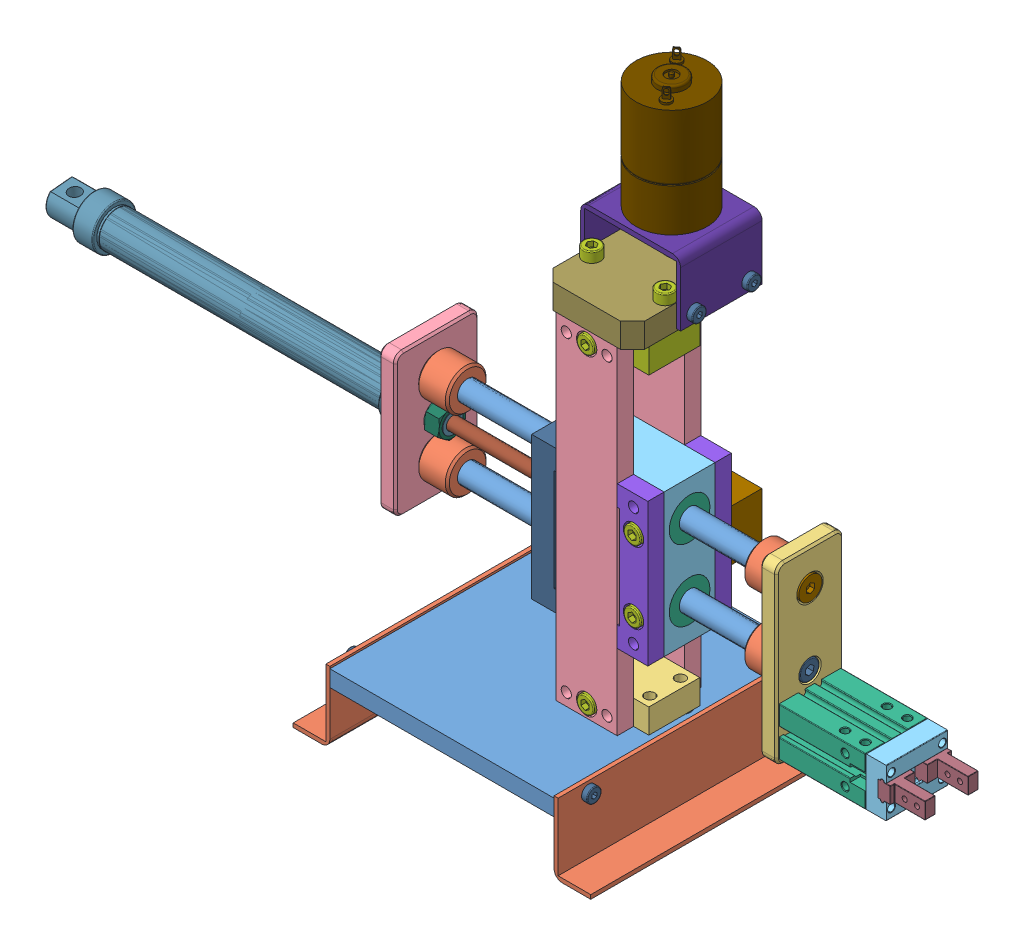
SolidWorks assembly handling, configuration Default. Lengths in mm.
Overall size (436.7 290 125).
70 component instances, 33 part files, 172 mates.
Components (placement in the parent):
- tam de lon-1: tam de lon [Default] at (42.5889 56.6685 101.1963) size (110 8 125)
- khoi do-1: khoi do [Default] at (98.4472 49.4552 163.6963) x (0 0 -1) z (-1 0 0) size (125 35 18)
- khoi do-2: khoi do [Default] at (-13.2695 49.4552 38.6963) x (0 0 1) z (1 0 0) size (125 35 18)
- mieng dem duoi-1: mieng dem duoi [Default] at (71.5889 64.6685 101.1963) size (45 12 25)
- thanh dan huong lon x2-1: thanh dan huong lon x2 [Default] at (71.5889 147.1685 113.6963) x (1 0 0) z (0 -1 0) size (30 8 165)
- thanh dan huong lon x2-2: thanh dan huong lon x2 [Default] at (71.5889 147.1685 88.6963) x (1 0 0) z (0 1 0) size (30 8 165)
- con truot s4 -1: con truot s4  [Default] at (79.0889 101.791 101.1963) x (-1 0 0) z (0 0 -1) size (45 70 25)
- bac lot-1: bac lot [Default] at (101.5889 119.291 101.1963) x (0 1 0) z (0 0 1) size (20 12 20)
- bac lot-2: bac lot [Default] at (101.5889 154.291 101.1963) x (0 1 0) z (0 0 1) size (20 12 20)
- bac lot-3: bac lot [Default] at (56.5889 154.291 101.1963) x (0 0.381849 -0.924225) z (0 -0.924225 -0.381849) size (20 12 20)
- bac lot-4: bac lot [Default] at (56.5889 119.291 101.1963) x (0 0.381849 -0.924225) z (0 -0.924225 -0.381849) size (20 12 20)
- mieng dem tren-1: mieng dem tren [Default] at (71.5889 217.6685 101.1963) size (45 12 25)
- thanh dan huong so 2 s4-3: thanh dan huong so 2 s4 [Default] at (94.0889 136.791 88.6963) x (-1 0 0) z (0 -1 0) size (15 8 70)
- thanh ngang-5: thanh ngang [Default] at (73.0889 133.791 65.6963) x (-1 0 0) z (0 1 0) size (57 15 25)
- tam dan huong-4: tam dan huong [Default] at (44.5889 136.791 101.1963) x (0 -1 0) z (0 0 1) size (70 12 41)
- dai oc-1: dai oc [Default] at (71.5889 136.791 65.6963) x (0 1 0) z (1 0 0) size (16 14 16)
- tam de nho-4: tam de nho [Default] at (71.5889 241.6685 90.6963) x (1 0 0) z (0 0 -1) size (45 12 62)
- dau kep truc vit-2: dau kep truc vit [Default] at (71.5889 256.8685 72.6963) x (-0.681909 0 -0.731437) z (-0.731437 0 0.681909) size (20 25 20)
- vong_dem-2: vong_dem [Default] at (71.5889 229.8685 72.6963) x (0.969315 0 0.245821) z (-0.245821 0 0.969315) size (19.6 2 19.6)
- vit me M8x150mm-2: vit me M8x150mm [Default] at (71.5889 171.8685 72.6963) x (0.994213 0 -0.107422) z (0 1 0) size (10.85 10.06 150.11)
- hex nut gradec_din-2: hex nut gradec_din [Hexagon Nut ISO 4034 - M8 - N] at (71.5889 221.9685 72.6963) x (-0.968146 0 0.250385) z (0 -1 0) size (13 15.01 7.9)
- de dong co-1: de dong co [Default] at (71.6847 246.1685 60.1963) x (1 0 0) z (0 -1 0) size (49 40 31)
- moto-1: moto [Default] at (71.7593 263.8856 80.1944) x (0 -1 0) z (0.022721 0 0.999742) size (78 35 35)
- chot dan huong-1: chot dan huong [Default] at (152.6856 154.291 101.1963) x (0 0.988897 -0.148604) z (0 0.148604 0.988897) size (10 175 10)
- chot dan huong-2: chot dan huong [Default] at (152.6856 119.291 101.1963) x (0 0.324021 0.94605) z (0 -0.94605 0.324021) size (10 175 10)
- bac chan-1: bac chan [Default] at (152.6856 154.291 101.1963) x (0 -0.987145 -0.159829) z (0 0.159829 -0.987145) size (20 15 20)
- bac chan-2: bac chan [Default] at (152.6856 119.291 101.1963) x (0 1 0) z (0 0 1) size (20 15 20)
- bac chan-3: bac chan [Default] at (-7.3144 154.291 101.1963) x (0 -0.034971 0.999388) z (0 -0.999388 -0.034971) size (20 15 20)
- bac chan-4: bac chan [Default] at (-7.3144 119.291 101.1963) x (0 0.99939 -0.03491) z (0 0.03491 0.99939) size (20 15 20)
- ban canh truoc-1: ban canh truoc [Default] at (152.6856 128.791 101.1963) x (0 0 -1) z (0 -1 0) size (33 8 86)
- ban canh sau-1: ban canh sau [Default] at (-22.3144 136.791 101.1963) x (0 0 -1) z (0 1 0) size (41 8 70)
- NMHZ2-16D-2: NMHZ2-16D [Default] at (145.6976 98.2332 123.6032) x (0 0 -1) z (1 0 0) size (30.6 23.6 52.5)
  - NMHZ2-16D Slipway-1: NMHZ2-16D Slipway [Default] at (22.4069 2.6078 57.488) size (30.1 23.6 10)
  - NMHZ2-16D cylinder-2: NMHZ2-16D cylinder [Default] at (22.4069 2.6078 14.988) size (30.6 23.6 42.5)
- socket head cap screw_din-2: socket head cap screw_din [DIN 912 M5 x 16 --- 16N] at (94.5889 154.291 79.8963) x (0 0 1) z (-1 0 0) size (21 8.5 8.5)
- socket head cap screw_din-3: socket head cap screw_din [DIN 912 M5 x 16 --- 16N] at (50.0889 130.291 66.3963) x (0 0 1) z (-1 0 0) size (21 8.5 8.5)
- socket head cap screw_din-4: socket head cap screw_din [DIN 912 M5 x 16 --- 16N] at (94.5889 143.291 66.3963) x (0 0 1) z (-1 0 0) size (21 8.5 8.5)
- socket head cap screw_din-5: socket head cap screw_din [DIN 912 M5 x 16 --- 16N] at (94.5889 119.291 79.8963) x (0 0 1) z (-1 0 0) size (21 8.5 8.5)
- socket head cap screw_din-6: socket head cap screw_din [DIN 912 M5 x 16 --- 16N] at (71.5889 70.6685 79.8963) x (0 0 1) z (-1 0 0) size (21 8.5 8.5)
- socket head cap screw_din-9: socket head cap screw_din [DIN 912 M5 x 8 --- 8N] at (71.5889 70.6685 122.4963) x (0 0 -1) z (1 0 0) size (13 8.5 8.5)
- socket head cap screw_din-10: socket head cap screw_din [DIN 912 M5 x 8 --- 8N] at (45.2889 107.791 108.6963) size (13 8.5 8.5)
- socket head cap screw_din-11: socket head cap screw_din [DIN 912 M5 x 8 --- 8N] at (45.2889 165.791 93.6963) size (13 8.5 8.5)
- thanh dan huong s4-1: thanh dan huong s4 [Default] at (94.0889 136.791 113.6963) x (-1 0 0) z (0 1 0) size (15 8 70)
- socket head cap screw_din-13: socket head cap screw_din [DIN 912 M5 x 12 --- 12N] at (94.5889 119.291 122.4963) x (0 0 -1) z (1 0 0) size (17 8.5 8.5)
- socket head cap screw_din-14: socket head cap screw_din [DIN 912 M5 x 12 --- 12N] at (94.5889 154.291 122.4963) x (0 0 -1) z (1 0 0) size (17 8.5 8.5)
- socket head cap screw_din-15: socket head cap screw_din [DIN 912 M5 x 12 --- 12N] at (53.5889 246.6685 101.1963) x (0 -1 0) z (0 0 1) size (17 8.5 8.5)
- socket head cap screw_din-16: socket head cap screw_din [DIN 912 M5 x 12 --- 12N] at (89.5889 246.6685 101.1963) x (0 -1 0) z (0 0 1) size (17 8.5 8.5)
- socket head cap screw_din-17: socket head cap screw_din [DIN 912 M5 x 12 --- 12N] at (71.5889 223.6685 79.8963) x (0 0 1) z (-1 0 0) size (17 8.5 8.5)
- socket head cap screw_din-18: socket head cap screw_din [DIN 912 M5 x 12 --- 12N] at (71.5889 223.6685 122.4963) x (0 0 -1) z (1 0 0) size (17 8.5 8.5)
- socket csink head cap screw 10642_din-2: socket csink head cap screw 10642_din [EN ISO 10642 - M6 x 8 - 8N] at (-30.5344 154.291 101.1963) x (1 0 0) z (0 0.02259 0.999745) size (8 11.34 11.34)
- socket csink head cap screw 10642_din-3: socket csink head cap screw 10642_din [EN ISO 10642 - M6 x 8 - 8N] at (160.9056 154.291 101.1963) x (-1 0 0) z (0 -0.022602 -0.999745) size (8 11.34 11.34)
- socket head thin cap screw_din-2: socket head thin cap screw_din [DIN 7984 - M6 x 10 --- 7N] at (160.4856 119.291 101.1963) x (-1 0 0) z (0 0.924225 0.381849) size (14 10 10)
- socket head thin cap screw_din-4: socket head thin cap screw_din [DIN 7984 - M6 x 10 --- 7N] at (-30.1144 119.291 101.1963) size (14 10 10)
- socket head thin cap screw_din-5: socket head thin cap screw_din [DIN 7984 - M4 x 6 --- 3.9N] at (-17.2111 60.6685 53.6963) size (8.8 7 7)
- socket head thin cap screw_din-6: socket head thin cap screw_din [DIN 7984 - M4 x 6 --- 3.9N] at (-17.2111 60.6685 148.6963) size (8.8 7 7)
- socket head thin cap screw_din-7: socket head thin cap screw_din [DIN 7984 - M4 x 6 --- 3.9N] at (102.3889 60.6685 53.6963) x (-1 0 0) z (0 0.924225 0.381849) size (8.8 7 7)
- socket head thin cap screw_din-8: socket head thin cap screw_din [DIN 7984 - M4 x 6 --- 3.9N] at (102.3889 60.6685 148.6963) x (-1 0 0) z (0 0.924225 0.381849) size (8.8 7 7)
- socket head thin cap screw_din-10: socket head thin cap screw_din [DIN 7984 - M4 x 12 --- 9.9N] at (154.2856 93.491 112.1963) size (14.8 7 7)
- socket head thin cap screw_din-11: socket head thin cap screw_din [DIN 7984 - M4 x 12 --- 9.9N] at (154.2856 108.491 90.1963) size (14.8 7 7)
- socket head thin cap screw_din-13: socket head thin cap screw_din [DIN 7984 - M4 x 6 --- 3.9N] at (98.9847 235.6685 66.6963) x (-1 0 0) z (0 0.924225 0.381849) size (8.8 7 7)
- socket head thin cap screw_din-14: socket head thin cap screw_din [DIN 7984 - M4 x 6 --- 3.9N] at (98.9847 235.6685 93.6963) x (-1 0 0) z (0 0.924225 0.381849) size (8.8 7 7)
- socket head thin cap screw_din-15: socket head thin cap screw_din [DIN 7984 - M4 x 6 --- 3.9N] at (44.3847 235.6685 66.6963) size (8.8 7 7)
- socket head thin cap screw_din-16: socket head thin cap screw_din [DIN 7984 - M4 x 6 --- 3.9N] at (44.3847 235.6685 93.6963) size (8.8 7 7)
- socket head thin cap screw_din-18: socket head thin cap screw_din [DIN 7984 - M3 x 5 --- 3.5N] at (67.1565 252.8685 67.942) x (0.681909 0 0.731437) z (0.731403 -0.009583 -0.681878) size (7 5.5 5.5)
- Rod-1: Rod [Default] at (-92.4392 136.791 101.1963) x (0 0.994852 -0.101337) z (0 -0.101337 -0.994852) size (6.2 165 6.2)
- Nut 5-1: Nut 5 [Default] at (55.0889 136.791 101.1963) x (0 -0.278581 0.960413) z (0 0.960413 0.278581) size (11.32 3 9.8)
- NMHZ2-16D air claw-1: NMHZ2-16D air claw [Default] at (211.1856 100.841 98.1463) x (0 0 -1) z (1 0 0) size (12 10 21)
- NMHZ2-16D air claw-2: NMHZ2-16D air claw [Default] at (211.1856 100.841 104.2463) x (0 0 1) z (1 0 0) size (12 10 21)
- 16 X 100 Cylinder bore-3: 16 X 100 Cylinder bore [Default] at (-110.5144 136.791 101.1963) x (0 -0.995265 -0.097204) z (-1 0 0) size (21.5 21.5 192)
- hex nut style 2 fine gradeab_din-4: hex nut style 2 fine gradeab_din [Hexagon Nut ISO 8674 - M8 x 1 - W - N] at (-14.8144 136.791 101.1963) x (0 0.810685 -0.585482) z (1 0 0) size (13 15.01 7.5)
Mates (geometry in assembly coordinates):
- Parallel1: parallel anti-aligned: plane of tam de lon-1 through (42.5889 64.6685 101.1963) normal (0 1 0); plane of khoi do-1 through (97.5889 30.6685 38.6963) normal (0 -1 0)
- Parallel2: parallel anti-aligned: plane of tam de lon-1 through (97.5889 64.6685 38.6963) normal (1 0 0); plane of khoi do-1 through (97.5889 30.6685 38.6963) normal (-1 0 0)
- Concentric1: concentric aligned: cylinder of tam de lon-1 through (82.5889 60.6685 53.6963) axis (1 0 0) radius 2.5; cylinder of khoi do-1 through (-25.4111 60.6685 53.6963) axis (1 0 0) radius 2.5
- Coincident1: coincident anti-aligned: plane of tam de lon-1 through (97.5889 64.6685 38.6963) normal (1 0 0); plane of khoi do-1 through (97.5889 30.6685 38.6963) normal (-1 0 0)
- Parallel3: parallel anti-aligned: plane of tam de lon-1 through (42.5889 64.6685 101.1963) normal (0 1 0); plane of khoi do-2 through (-12.4111 30.6685 163.6963) normal (0 -1 0)
- Parallel4: parallel anti-aligned: plane of tam de lon-1 through (-12.4111 64.6685 38.6963) normal (-1 0 0); plane of khoi do-2 through (-12.4111 30.6685 163.6963) normal (1 0 0)
- Concentric2: concentric aligned: cylinder of tam de lon-1 through (2.5889 60.6685 148.6963) axis (-1 0 0) radius 2.5; cylinder of khoi do-2 through (110.5889 60.6685 148.6963) axis (-1 0 0) radius 2.5
- Coincident2: coincident anti-aligned: plane of tam de lon-1 through (-12.4111 64.6685 38.6963) normal (-1 0 0); plane of khoi do-2 through (-12.4111 30.6685 163.6963) normal (1 0 0)
- Concentric3: concentric aligned: cylinder of tam de lon-1 through (89.5889 56.6685 93.6963) axis (0 1 0) radius 2.75; cylinder of mieng dem duoi-1 through (89.5889 64.6685 93.6963) axis (0 1 0) radius 2.5
- Concentric4: concentric aligned: cylinder of tam de lon-1 through (53.5889 56.6685 108.6963) axis (0 1 0) radius 2.75; cylinder of mieng dem duoi-1 through (53.5889 64.6685 108.6963) axis (0 1 0) radius 2.5
- Coincident3: coincident anti-aligned: plane of tam de lon-1 through (42.5889 64.6685 101.1963) normal (0 1 0); plane of mieng dem duoi-1 through (71.5889 64.6685 101.1963) normal (0 -1 0)
- Parallel6: parallel anti-aligned: plane of mieng dem duoi-1 through (71.5889 76.6685 101.1963) normal (0 1 0); plane of thanh dan huong lon x2-1 through (56.5889 64.6685 121.6963) normal (0 -1 0)
- Parallel7: parallel anti-aligned: plane of mieng dem duoi-1 through (49.0889 76.6685 113.6963) normal (0 0 1); plane of thanh dan huong lon x2-1 through (71.5889 147.1685 113.6963) normal (0 0 -1)
- Concentric5: concentric anti-aligned: cylinder of mieng dem duoi-1 through (81.5889 70.6685 160.6963) axis (0 0 -1) radius 2.5; cylinder of thanh dan huong lon x2-1 through (81.5889 70.6685 80.4963) axis (0 0 1) radius 2.5
- Coincident4: coincident anti-aligned: plane of mieng dem duoi-1 through (49.0889 76.6685 113.6963) normal (0 0 1); plane of thanh dan huong lon x2-1 through (71.5889 147.1685 113.6963) normal (0 0 -1)
- Parallel8: parallel anti-aligned: plane of mieng dem duoi-1 through (71.5889 76.6685 101.1963) normal (0 1 0); plane of thanh dan huong lon x2-2 through (56.5889 64.6685 80.6963) normal (0 -1 0)
- Parallel9: parallel anti-aligned: plane of mieng dem duoi-1 through (49.0889 76.6685 88.6963) normal (0 0 -1); plane of thanh dan huong lon x2-2 through (71.5889 147.1685 88.6963) normal (0 0 1)
- Concentric6: concentric aligned: cylinder of mieng dem duoi-1 through (81.5889 70.6685 160.6963) axis (0 0 -1) radius 2.5; cylinder of thanh dan huong lon x2-2 through (81.5889 70.6685 121.8963) axis (0 0 -1) radius 2.5
- Coincident5: coincident anti-aligned: plane of mieng dem duoi-1 through (49.0889 76.6685 88.6963) normal (0 0 -1); plane of thanh dan huong lon x2-2 through (71.5889 147.1685 88.6963) normal (0 0 1)
- Parallel10: parallel anti-aligned: plane of mieng dem duoi-1 through (94.0889 76.6685 88.6963) normal (1 0 0); plane of con truot s4 -1 through (56.5889 171.791 113.6963) normal (-1 0 0)
- Parallel11: parallel aligned: plane of mieng dem duoi-1 through (71.5889 76.6685 101.1963) normal (0 1 0); plane of con truot s4 -1 through (79.0889 171.791 101.1963) normal (0 1 0)
- Coincident6: coincident anti-aligned: plane of thanh dan huong lon x2-2 through (71.5889 147.1685 88.6963) normal (0 0 1); plane of con truot s4 -1 through (101.5889 171.791 88.6963) normal (0 0 -1)
- Concentric7: concentric anti-aligned: cylinder of con truot s4 -1 through (126.5889 119.291 101.1963) axis (-1 0 0) radius 6; cylinder of bac lot-1 through (89.5889 119.291 101.1963) axis (1 0 0) radius 6
- Coincident14: coincident anti-aligned: plane of con truot s4 -1 through (99.5889 119.291 101.1963) normal (1 0 0); plane of bac lot-1 through (99.5889 119.291 101.1963) normal (-1 0 0)
- Concentric8: concentric anti-aligned: cylinder of con truot s4 -1 through (126.5889 154.291 101.1963) axis (-1 0 0) radius 6; cylinder of bac lot-2 through (89.5889 154.291 101.1963) axis (1 0 0) radius 6
- Coincident15: coincident anti-aligned: plane of con truot s4 -1 through (99.5889 154.291 101.1963) normal (1 0 0); plane of bac lot-2 through (99.5889 154.291 101.1963) normal (-1 0 0)
- Concentric9: concentric aligned: cylinder of con truot s4 -1 through (126.5889 154.291 101.1963) axis (-1 0 0) radius 6; cylinder of bac lot-3 through (68.5889 154.291 101.1963) axis (-1 0 0) radius 6
- Coincident16: coincident anti-aligned: plane of con truot s4 -1 through (58.5889 154.291 101.1963) normal (-1 0 0); plane of bac lot-3 through (58.5889 154.291 101.1963) normal (1 0 0)
- Concentric10: concentric aligned: cylinder of con truot s4 -1 through (126.5889 119.291 101.1963) axis (-1 0 0) radius 6; cylinder of bac lot-4 through (68.5889 119.291 101.1963) axis (-1 0 0) radius 6
- Coincident18: coincident anti-aligned: plane of con truot s4 -1 through (58.5889 119.291 101.1963) normal (-1 0 0); plane of bac lot-4 through (58.5889 119.291 101.1963) normal (1 0 0)
- Parallel23: parallel aligned: plane of thanh dan huong lon x2-2 through (56.5889 229.6685 80.6963) normal (0 1 0); plane of mieng dem tren-1 through (71.5889 229.6685 101.1963) normal (0 1 0)
- Concentric12: concentric aligned: cylinder of thanh dan huong lon x2-2 through (61.5889 223.6685 121.8963) axis (0 0 -1) radius 2.5; cylinder of mieng dem tren-1 through (61.5889 223.6685 160.6963) axis (0 0 -1) radius 2.5
- Coincident21: coincident anti-aligned: plane of thanh dan huong lon x2-2 through (71.5889 147.1685 88.6963) normal (0 0 1); plane of mieng dem tren-1 through (49.0889 229.6685 88.6963) normal (0 0 -1)
- Parallel38: parallel aligned: plane of con truot s4 -1 through (79.0889 171.791 101.1963) normal (0 1 0); plane of thanh dan huong so 2 s4-3 through (101.5889 171.791 80.6963) normal (0 1 0)
- Parallel39: parallel anti-aligned: plane of con truot s4 -1 through (101.5889 171.791 88.6963) normal (0 0 -1); plane of thanh dan huong so 2 s4-3 through (94.0889 136.791 88.6963) normal (0 0 1)
- Coincident32: coincident aligned: plane of con truot s4 -1 through (79.0889 171.791 101.1963) normal (0 1 0); plane of thanh dan huong so 2 s4-3 through (101.5889 171.791 80.6963) normal (0 1 0)
- Coincident33: coincident aligned: plane of con truot s4 -1 through (101.5889 171.791 113.6963) normal (1 0 0); plane of thanh dan huong so 2 s4-3 through (101.5889 171.791 80.6963) normal (1 0 0)
- Coincident34: coincident anti-aligned: plane of con truot s4 -1 through (101.5889 171.791 88.6963) normal (0 0 -1); plane of thanh dan huong so 2 s4-3 through (94.0889 136.791 88.6963) normal (0 0 1)
- Coincident36: coincident anti-aligned: plane of thanh dan huong lon x2-2 through (86.5889 64.6685 80.6963) normal (1 0 0); plane of thanh dan huong so 2 s4-3 through (86.5889 171.791 80.6963) normal (-1 0 0)
- Parallel42: parallel anti-aligned: plane of thanh dan huong so 2 s4-3 through (101.5889 171.791 80.6963) normal (0 1 0); plane of thanh ngang-5 through (101.5889 124.291 80.6963) normal (0 -1 0)
- Concentric26: concentric aligned: cylinder of thanh dan huong so 2 s4-3 through (94.5889 143.291 152.8963) axis (0 0 -1) radius 2.5; cylinder of thanh ngang-5 through (94.5889 143.291 124.3963) axis (0 0 -1) radius 2.75
- Parallel46: parallel aligned: plane of con truot s4 -1 through (79.0889 171.791 101.1963) normal (0 1 0); plane of tam dan huong-4 through (56.5889 171.791 80.6963) normal (0 1 0)
- Parallel47: parallel anti-aligned: plane of con truot s4 -1 through (56.5889 171.791 113.6963) normal (-1 0 0); plane of tam dan huong-4 through (55.5889 161.791 33.6963) normal (1 0 0)
- Coincident40: coincident anti-aligned: plane of con truot s4 -1 through (56.5889 171.791 113.6963) normal (-1 0 0); plane of tam dan huong-4 through (56.5889 136.791 101.1963) normal (1 0 0)
- Concentric29: concentric aligned: cylinder of con truot s4 -1 through (71.5889 165.791 93.6963) axis (-1 0 0) radius 2.5; cylinder of tam dan huong-4 through (132.5889 165.791 93.6963) axis (-1 0 0) radius 2.75
- Coincident41: coincident anti-aligned: plane of thanh dan huong so 2 s4-3 through (94.0889 136.791 80.6963) normal (0 0 -1); plane of thanh ngang-5 through (73.0889 133.791 80.6963) normal (0 0 1)
- Parallel48: parallel anti-aligned: plane of thanh ngang-5 through (73.0889 133.791 65.6963) normal (0 0 -1); plane of dai oc-1 through (80.1238 157.791 79.6963) normal (0 0 1)
- Concentric30: concentric anti-aligned: cylinder of thanh ngang-5 through (71.5889 -21.709 72.6963) axis (0 1 0) radius 5; cylinder of dai oc-1 through (71.5889 157.791 72.6963) axis (0 -1 0) radius 4
- Concentric31: concentric aligned: cylinder of thanh ngang-5 through (71.5889 136.791 236.6963) axis (0 0 -1) radius 8; cylinder of dai oc-1 through (71.5889 136.791 79.6963) axis (0 0 -1) radius 8
- Parallel53: parallel anti-aligned: plane of mieng dem tren-1 through (71.5889 229.6685 101.1963) normal (0 1 0); plane of tam de nho-4 through (71.5889 229.6685 90.6963) normal (0 -1 0)
- Parallel54: parallel anti-aligned: plane of mieng dem tren-1 through (94.0889 229.6685 88.6963) normal (1 0 0); plane of tam de nho-4 through (49.0889 229.6685 121.6963) normal (-1 0 0)
- Concentric32: concentric anti-aligned: cylinder of mieng dem tren-1 through (53.5889 157.6685 101.1963) axis (0 1 0) radius 2.5; cylinder of tam de nho-4 through (53.5889 241.6685 101.1963) axis (0 -1 0) radius 2.75
- Coincident45: coincident anti-aligned: plane of mieng dem tren-1 through (71.5889 229.6685 101.1963) normal (0 1 0); plane of tam de nho-4 through (71.5889 229.6685 90.6963) normal (0 -1 0)
- Parallel55: parallel anti-aligned: plane of tam de nho-4 through (71.5889 241.6685 90.6963) normal (0 1 0); plane of dau kep truc vit-2 through (71.5889 231.8685 72.6963) normal (0 -1 0)
- Concentric33: concentric aligned: cylinder of tam de nho-4 through (71.5889 241.6685 72.6963) axis (0 -1 0) radius 7; cylinder of dau kep truc vit-2 through (71.5889 241.6685 72.6963) axis (0 -1 0) radius 7
- Coincident46: coincident anti-aligned: plane of tam de nho-4 through (71.5889 241.6685 90.6963) normal (0 1 0); plane of dau kep truc vit-2 through (71.5889 241.6685 72.6963) normal (0 -1 0)
- Concentric34: concentric aligned: cylinder of dau kep truc vit-2 through (71.5889 246.8685 72.6963) axis (0 -1 0) radius 4; cylinder of vong_dem-2 through (71.5889 231.8685 72.6963) axis (0 -1 0) radius 4.25
- Coincident47: coincident anti-aligned: plane of dau kep truc vit-2 through (71.5889 231.8685 72.6963) normal (0 -1 0); plane of vong_dem-2 through (71.5889 231.8685 72.6963) normal (0 1 0)
- Concentric35: concentric anti-aligned: cylinder of dau kep truc vit-2 through (71.5889 246.8685 72.6963) axis (0 -1 0) radius 4; cylinder of vit me M8x150mm-2 through (71.5889 171.8685 72.6963) axis (0 1 0) radius 3.933
- Coincident48: coincident anti-aligned: plane of dau kep truc vit-2 through (71.5889 246.8685 72.6963) normal (0 -1 0); plane of vit me M8x150mm-2 through (71.5889 246.8685 72.6963) normal (0 1 0)
- Concentric37: concentric anti-aligned: cylinder of vit me M8x150mm-2 through (71.5889 171.8685 72.6963) axis (0 1 0) radius 3.933; cylinder of hex nut gradec_din-2 through (71.5889 229.8685 72.6963) axis (0 -1 0) radius 3.4
- Coincident49: coincident anti-aligned: plane of vong_dem-2 through (71.5889 229.8685 72.6963) normal (0 -1 0); plane of hex nut gradec_din-2 through (69.7096 229.8685 65.4298) normal (0 1 0)
- Lock1: lock: unknown of vit me M8x150mm-2; unknown of hex nut gradec_din-2
- Lock2: lock: unknown of dau kep truc vit-2; unknown of hex nut gradec_din-2
- Concentric38: concentric anti-aligned: cylinder of tam de nho-4 through (78.0889 235.6685 66.6963) axis (1 0 0) radius 2; cylinder of de dong co-1 through (123.1847 235.6685 66.6963) axis (-1 0 0) radius 2.25
- Concentric39: concentric anti-aligned: cylinder of tam de nho-4 through (78.0889 235.6685 93.6963) axis (1 0 0) radius 2; cylinder of de dong co-1 through (123.1847 235.6685 93.6963) axis (-1 0 0) radius 2.25
- Coincident50: coincident anti-aligned: plane of tam de nho-4 through (94.0889 229.6685 121.6963) normal (1 0 0); plane of de dong co-1 through (94.0889 259.3217 523.1963) normal (-1 0 0)
- Parallel56: parallel anti-aligned: plane of de dong co-1 through (47.1847 261.6685 100.1963) normal (0 1 0); plane of moto-1 through (71.7593 261.6685 80.1944) normal (0 -1 0)
- Concentric40: concentric aligned: cylinder of dau kep truc vit-2 through (71.5889 245.8685 72.6963) axis (0 1 0) radius 2.75; cylinder of moto-1 through (71.5889 242.6685 72.6963) axis (0 1 0) radius 2.75
- Coincident52: coincident anti-aligned: plane of de dong co-1 through (47.1847 261.6685 100.1963) normal (0 1 0); plane of moto-1 through (71.7593 261.6685 80.1944) normal (0 -1 0)
- Lock3: lock: unknown of de dong co-1; unknown of moto-1
- Concentric41: concentric anti-aligned: cylinder of bac lot-2 through (116.5889 154.291 101.1963) axis (-1 0 0) radius 5; cylinder of chot dan huong-1 through (-120.3144 154.291 101.1963) axis (1 0 0) radius 5
- Concentric42: concentric anti-aligned: cylinder of bac lot-1 through (116.5889 119.291 101.1963) axis (-1 0 0) radius 5; cylinder of chot dan huong-2 through (-120.3144 119.291 101.1963) axis (1 0 0) radius 5
- Concentric43: concentric anti-aligned: cylinder of chot dan huong-1 through (-120.3144 154.291 101.1963) axis (1 0 0) radius 5; cylinder of bac chan-1 through (152.6856 154.291 101.1963) axis (-1 0 0) radius 5
- Coincident53: coincident aligned: plane of chot dan huong-1 through (152.6856 154.291 101.1963) normal (1 0 0); plane of bac chan-1 through (152.6856 154.291 101.1963) normal (1 0 0)
- Concentric44: concentric anti-aligned: cylinder of chot dan huong-2 through (-120.3144 119.291 101.1963) axis (1 0 0) radius 5; cylinder of bac chan-2 through (152.6856 119.291 101.1963) axis (-1 0 0) radius 5
- Coincident54: coincident aligned: plane of chot dan huong-2 through (152.6856 119.291 101.1963) normal (1 0 0); plane of bac chan-2 through (152.6856 119.291 101.1963) normal (1 0 0)
- Concentric45: concentric anti-aligned: cylinder of chot dan huong-1 through (-120.3144 154.291 101.1963) axis (1 0 0) radius 5; cylinder of bac chan-3 through (-7.3144 154.291 101.1963) axis (-1 0 0) radius 5
- Coincident55: coincident aligned: plane of chot dan huong-1 through (-22.3144 154.291 101.1963) normal (-1 0 0); plane of bac chan-3 through (-22.3144 154.291 101.1963) normal (-1 0 0)
- Coincident57: coincident aligned: plane of chot dan huong-2 through (-22.3144 119.291 101.1963) normal (-1 0 0); plane of bac chan-4 through (-22.3144 119.291 101.1963) normal (-1 0 0)
- Concentric47: concentric aligned: cylinder of chot dan huong-1 through (132.6856 154.291 101.1963) axis (1 0 0) radius 3; cylinder of ban canh truoc-1 through (152.6856 154.291 101.1963) axis (1 0 0) radius 3.3
- Concentric48: concentric aligned: cylinder of chot dan huong-2 through (132.6856 119.291 101.1963) axis (1 0 0) radius 3; cylinder of ban canh truoc-1 through (152.6856 119.291 101.1963) axis (1 0 0) radius 3.3
- Coincident58: coincident anti-aligned: plane of chot dan huong-1 through (152.6856 154.291 101.1963) normal (1 0 0); plane of ban canh truoc-1 through (152.6856 128.791 101.1963) normal (-1 0 0)
- Coincident59: coincident anti-aligned: plane of chot dan huong-2 through (152.6856 119.291 101.1963) normal (1 0 0); plane of ban canh truoc-1 through (152.6856 128.791 101.1963) normal (-1 0 0)
- Concentric49: concentric aligned: cylinder of chot dan huong-1 through (-2.3144 154.291 101.1963) axis (-1 0 0) radius 3; cylinder of ban canh sau-1 through (-22.3144 154.291 101.1963) axis (-1 0 0) radius 3.3
- Concentric50: concentric aligned: cylinder of chot dan huong-2 through (-2.3144 119.291 101.1963) axis (-1 0 0) radius 3; cylinder of ban canh sau-1 through (-22.3144 119.291 101.1963) axis (-1 0 0) radius 3.3
- Coincident60: coincident anti-aligned: plane of chot dan huong-1 through (-22.3144 154.291 101.1963) normal (-1 0 0); plane of ban canh sau-1 through (-22.3144 136.791 101.1963) normal (1 0 0)
- Coincident61: coincident anti-aligned: plane of chot dan huong-2 through (-22.3144 119.291 101.1963) normal (-1 0 0); plane of ban canh sau-1 through (-22.3144 136.791 101.1963) normal (1 0 0)
- Concentric55: concentric anti-aligned: cylinder of ban canh truoc-1 through (152.6856 93.491 112.1963) axis (1 0 0) radius 2.25; cylinder of NMHZ2-16D-2/NMHZ2-16D cylinder-2 through (175.6856 93.491 112.1963) axis (-1 0 0) radius 2
- Concentric56: concentric anti-aligned: cylinder of ban canh truoc-1 through (152.6856 108.491 90.1963) axis (1 0 0) radius 2.25; cylinder of NMHZ2-16D-2/NMHZ2-16D cylinder-2 through (175.6856 108.491 90.1963) axis (-1 0 0) radius 2
- Coincident62: coincident anti-aligned: plane of ban canh truoc-1 through (160.6856 128.791 101.1963) normal (1 0 0); plane of NMHZ2-16D-2/NMHZ2-16D cylinder-2 through (160.6856 100.841 101.1963) normal (-1 0 0)
- Concentric57: concentric anti-aligned: cylinder of chot dan huong-2 through (-120.3144 119.291 101.1963) axis (1 0 0) radius 5; cylinder of bac chan-4 through (-7.3144 119.291 101.1963) axis (-1 0 0) radius 5
- Concentric61: concentric aligned: cylinder of thanh dan huong so 2 s4-3 through (94.5889 154.291 88.6963) axis (0 0 -1) radius 2.75; cylinder of socket head cap screw_din-2 through (94.5889 154.291 48.1463) axis (0 0 -1) radius 4.25
- Coincident66: coincident anti-aligned: plane of thanh dan huong so 2 s4-3 through (94.5889 154.291 84.8963) normal (0 0 -1); plane of socket head cap screw_din-2 through (94.5889 158.541 84.8963) normal (0 0 1)
- Concentric62: concentric aligned: cylinder of thanh ngang-5 through (50.0889 130.291 71.3963) axis (0 0 -1) radius 5; cylinder of socket head cap screw_din-3 through (50.0889 130.291 34.6463) axis (0 0 -1) radius 4.25
- Coincident67: coincident anti-aligned: plane of thanh ngang-5 through (50.0889 130.291 71.3963) normal (0 0 -1); plane of socket head cap screw_din-3 through (50.0889 134.541 71.3963) normal (0 0 1)
- Concentric63: concentric aligned: cylinder of thanh ngang-5 through (94.5889 143.291 124.3963) axis (0 0 -1) radius 2.75; cylinder of socket head cap screw_din-4 through (94.5889 143.291 34.6463) axis (0 0 -1) radius 4.25
- Coincident68: coincident anti-aligned: plane of thanh ngang-5 through (94.5889 143.291 71.3963) normal (0 0 -1); plane of socket head cap screw_din-4 through (94.5889 147.541 71.3963) normal (0 0 1)
- Concentric64: concentric aligned: cylinder of thanh dan huong so 2 s4-3 through (94.5889 119.291 88.6963) axis (0 0 -1) radius 2.75; cylinder of socket head cap screw_din-5 through (94.5889 119.291 48.1463) axis (0 0 -1) radius 4.25
- Coincident69: coincident anti-aligned: plane of thanh dan huong so 2 s4-3 through (94.5889 119.291 84.8963) normal (0 0 -1); plane of socket head cap screw_din-5 through (94.5889 123.541 84.8963) normal (0 0 1)
- Concentric651: concentric aligned: cylinder of thanh dan huong lon x2-2 through (71.5889 70.6685 88.6963) axis (0 0 -1) radius 2.75; cylinder of socket head cap screw_din-6 through (71.5889 70.6685 48.1463) axis (0 0 -1) radius 4.25
- Coincident701: coincident anti-aligned: plane of thanh dan huong lon x2-2 through (71.5889 70.6685 84.8963) normal (0 0 -1); plane of socket head cap screw_din-6 through (71.5889 74.9185 84.8963) normal (0 0 1)
- Concentric66: concentric aligned: cylinder of thanh dan huong lon x2-1 through (71.5889 70.6685 113.6963) axis (0 0 1) radius 2.75; cylinder of socket head cap screw_din-9 through (71.5889 70.6685 154.2463) axis (0 0 1) radius 4.25
- Coincident71: coincident anti-aligned: plane of thanh dan huong lon x2-1 through (71.5889 70.6685 117.4963) normal (0 0 1); plane of socket head cap screw_din-9 through (71.5889 74.9185 117.4963) normal (0 0 -1)
- Concentric67: concentric aligned: cylinder of tam dan huong-4 through (132.5889 107.791 108.6963) axis (-1 0 0) radius 2.75; cylinder of socket head cap screw_din-10 through (13.5389 107.791 108.6963) axis (-1 0 0) radius 4.25
- Coincident72: coincident anti-aligned: plane of tam dan huong-4 through (50.2889 107.791 108.6963) normal (-1 0 0); plane of socket head cap screw_din-10 through (50.2889 112.041 108.6963) normal (1 0 0)
- Concentric68: concentric aligned: cylinder of tam dan huong-4 through (132.5889 165.791 93.6963) axis (-1 0 0) radius 2.75; cylinder of socket head cap screw_din-11 through (13.5389 165.791 93.6963) axis (-1 0 0) radius 4.25
- Coincident73: coincident anti-aligned: plane of tam dan huong-4 through (50.2889 165.791 93.6963) normal (-1 0 0); plane of socket head cap screw_din-11 through (50.2889 170.041 93.6963) normal (1 0 0)
- Parallel62: parallel aligned: plane of con truot s4 -1 through (101.5889 171.791 113.6963) normal (0 0 1); plane of thanh dan huong s4-1 through (94.0889 136.791 121.6963) normal (0 0 1)
- Parallel63: parallel aligned: plane of con truot s4 -1 through (101.5889 171.791 113.6963) normal (1 0 0); plane of thanh dan huong s4-1 through (101.5889 101.791 121.6963) normal (1 0 0)
- Concentric71: concentric anti-aligned: cylinder of con truot s4 -1 through (94.5889 119.291 124.6963) axis (0 0 -1) radius 2.5; cylinder of thanh dan huong s4-1 through (94.5889 119.291 113.6963) axis (0 0 1) radius 2.75
- Coincident76: coincident anti-aligned: plane of con truot s4 -1 through (101.5889 171.791 113.6963) normal (0 0 1); plane of thanh dan huong s4-1 through (94.0889 136.791 113.6963) normal (0 0 -1)
- Concentric72: concentric aligned: cylinder of thanh dan huong s4-1 through (94.5889 119.291 113.6963) axis (0 0 1) radius 2.75; cylinder of socket head cap screw_din-13 through (94.5889 119.291 154.2463) axis (0 0 1) radius 4.25
- Coincident77: coincident anti-aligned: plane of thanh dan huong s4-1 through (94.5889 119.291 117.4963) normal (0 0 1); plane of socket head cap screw_din-13 through (94.5889 123.541 117.4963) normal (0 0 -1)
- Concentric73: concentric aligned: cylinder of thanh dan huong s4-1 through (94.5889 154.291 113.6963) axis (0 0 1) radius 2.75; cylinder of socket head cap screw_din-14 through (94.5889 154.291 154.2463) axis (0 0 1) radius 4.25
- Coincident78: coincident anti-aligned: plane of thanh dan huong s4-1 through (94.5889 154.291 117.4963) normal (0 0 1); plane of socket head cap screw_din-14 through (94.5889 158.541 117.4963) normal (0 0 -1)
- Concentric74: concentric anti-aligned: cylinder of tam de nho-4 through (53.5889 241.6685 101.1963) axis (0 -1 0) radius 2.75; cylinder of socket head cap screw_din-15 through (53.5889 278.4185 101.1963) axis (0 1 0) radius 4.25
- Coincident79: coincident anti-aligned: plane of tam de nho-4 through (71.5889 241.6685 90.6963) normal (0 1 0); plane of socket head cap screw_din-15 through (57.8389 241.6685 101.1963) normal (0 -1 0)
- Concentric75: concentric anti-aligned: cylinder of tam de nho-4 through (89.5889 241.6685 101.1963) axis (0 -1 0) radius 2.75; cylinder of socket head cap screw_din-16 through (89.5889 278.4185 101.1963) axis (0 1 0) radius 4.25
- Coincident80: coincident anti-aligned: plane of tam de nho-4 through (71.5889 241.6685 90.6963) normal (0 1 0); plane of socket head cap screw_din-16 through (93.8389 241.6685 101.1963) normal (0 -1 0)
- Concentric76: concentric aligned: cylinder of thanh dan huong lon x2-2 through (71.5889 223.6685 84.8963) axis (0 0 -1) radius 5; cylinder of socket head cap screw_din-17 through (71.5889 223.6685 48.1463) axis (0 0 -1) radius 4.25
- Coincident81: coincident anti-aligned: plane of thanh dan huong lon x2-2 through (71.5889 223.6685 84.8963) normal (0 0 -1); plane of socket head cap screw_din-17 through (71.5889 227.9185 84.8963) normal (0 0 1)
- Concentric77: concentric aligned: cylinder of thanh dan huong lon x2-1 through (71.5889 223.6685 113.6963) axis (0 0 1) radius 2.75; cylinder of socket head cap screw_din-18 through (71.5889 223.6685 154.2463) axis (0 0 1) radius 4.25
- Coincident82: coincident anti-aligned: plane of thanh dan huong lon x2-1 through (71.5889 223.6685 117.4963) normal (0 0 1); plane of socket head cap screw_din-18 through (71.5889 227.9185 117.4963) normal (0 0 -1)
- Coincident83: coincident aligned: cone of ban canh sau-1 through (-27.1144 154.291 101.1963) axis (1 0 0); cone of socket csink head cap screw 10642_din-2 through (-29.4844 154.291 101.1963) axis (1 0 0)
- Coincident84: coincident aligned: cone of ban canh truoc-1 through (157.4856 154.291 101.1963) axis (-1 0 0); cone of socket csink head cap screw 10642_din-3 through (159.8556 154.291 101.1963) axis (-1 0 0)
- Concentric78: concentric aligned: cylinder of ban canh truoc-1 through (152.6856 119.291 101.1963) axis (1 0 0) radius 3.3; cylinder of socket head thin cap screw_din-2 through (192.2356 119.291 101.1963) axis (1 0 0) radius 5
- Coincident85: coincident anti-aligned: plane of ban canh truoc-1 through (156.4856 119.291 101.1963) normal (1 0 0); plane of socket head thin cap screw_din-2 through (156.4856 117.3817 105.8174) normal (-1 0 0)
- Concentric79: concentric aligned: cylinder of ban canh sau-1 through (-22.3144 119.291 101.1963) axis (-1 0 0) radius 3.3; cylinder of socket head thin cap screw_din-4 through (-61.8644 119.291 101.1963) axis (-1 0 0) radius 5
- Coincident86: coincident anti-aligned: plane of ban canh sau-1 through (-26.1144 119.291 101.1963) normal (-1 0 0); plane of socket head thin cap screw_din-4 through (-26.1144 124.291 101.1963) normal (1 0 0)
- Concentric80: concentric aligned: cylinder of khoi do-2 through (110.5889 60.6685 53.6963) axis (-1 0 0) radius 2.5; cylinder of socket head thin cap screw_din-5 through (-48.9611 60.6685 53.6963) axis (-1 0 0) radius 3.5
- Coincident87: coincident anti-aligned: plane of khoi do-2 through (-14.4111 32.6685 163.6963) normal (-1 0 0); plane of socket head thin cap screw_din-5 through (-14.4111 64.1685 53.6963) normal (1 0 0)
- Concentric81: concentric aligned: cylinder of khoi do-2 through (110.5889 60.6685 148.6963) axis (-1 0 0) radius 2.5; cylinder of socket head thin cap screw_din-6 through (-48.9611 60.6685 148.6963) axis (-1 0 0) radius 3.5
- Coincident88: coincident anti-aligned: plane of khoi do-2 through (-14.4111 32.6685 163.6963) normal (-1 0 0); plane of socket head thin cap screw_din-6 through (-14.4111 64.1685 148.6963) normal (1 0 0)
- Concentric82: concentric aligned: cylinder of khoi do-1 through (-25.4111 60.6685 53.6963) axis (1 0 0) radius 2.5; cylinder of socket head thin cap screw_din-7 through (134.1389 60.6685 53.6963) axis (1 0 0) radius 3.5
- Coincident89: coincident anti-aligned: plane of khoi do-1 through (99.5889 32.6685 38.6963) normal (1 0 0); plane of socket head thin cap screw_din-7 through (99.5889 59.332 56.9311) normal (-1 0 0)
- Concentric83: concentric aligned: cylinder of khoi do-1 through (-25.4111 60.6685 148.6963) axis (1 0 0) radius 2.5; cylinder of socket head thin cap screw_din-8 through (134.1389 60.6685 148.6963) axis (1 0 0) radius 3.5
- Coincident90: coincident anti-aligned: plane of khoi do-1 through (99.5889 32.6685 38.6963) normal (1 0 0); plane of socket head thin cap screw_din-8 through (99.5889 59.332 151.9311) normal (-1 0 0)
- Concentric84: concentric anti-aligned: cylinder of ban canh truoc-1 through (152.6856 93.491 112.1963) axis (1 0 0) radius 2.25; cylinder of socket head thin cap screw_din-10 through (122.5356 93.491 112.1963) axis (-1 0 0) radius 3.5
- Coincident91: coincident anti-aligned: plane of ban canh truoc-1 through (157.0856 93.491 112.1963) normal (-1 0 0); plane of socket head thin cap screw_din-10 through (157.0856 96.991 112.1963) normal (1 0 0)
- Concentric85: concentric aligned: cylinder of ban canh truoc-1 through (157.0856 108.491 90.1963) axis (-1 0 0) radius 4; cylinder of socket head thin cap screw_din-11 through (122.5356 108.491 90.1963) axis (-1 0 0) radius 3.5
- Coincident92: coincident anti-aligned: plane of ban canh truoc-1 through (157.0856 108.491 90.1963) normal (-1 0 0); plane of socket head thin cap screw_din-11 through (157.0856 111.991 90.1963) normal (1 0 0)
- Concentric86: concentric anti-aligned: cylinder of de dong co-1 through (123.1847 235.6685 66.6963) axis (-1 0 0) radius 2.25; cylinder of socket head thin cap screw_din-13 through (130.7347 235.6685 66.6963) axis (1 0 0) radius 3.5
- Coincident93: coincident anti-aligned: plane of de dong co-1 through (96.1847 261.6685 100.1963) normal (1 0 0); plane of socket head thin cap screw_din-13 through (96.1847 234.332 69.9311) normal (-1 0 0)
- Concentric87: concentric anti-aligned: cylinder of de dong co-1 through (123.1847 235.6685 93.6963) axis (-1 0 0) radius 2.25; cylinder of socket head thin cap screw_din-14 through (130.7347 235.6685 93.6963) axis (1 0 0) radius 3.5
- Coincident94: coincident anti-aligned: plane of de dong co-1 through (96.1847 261.6685 100.1963) normal (1 0 0); plane of socket head thin cap screw_din-14 through (96.1847 234.332 96.9311) normal (-1 0 0)
- Concentric88: concentric aligned: cylinder of de dong co-1 through (123.1847 235.6685 66.6963) axis (-1 0 0) radius 2.25; cylinder of socket head thin cap screw_din-15 through (12.6347 235.6685 66.6963) axis (-1 0 0) radius 3.5
- Coincident95: coincident anti-aligned: plane of de dong co-1 through (47.1847 261.6685 100.1963) normal (-1 0 0); plane of socket head thin cap screw_din-15 through (47.1847 239.1685 66.6963) normal (1 0 0)
- Concentric89: concentric aligned: cylinder of de dong co-1 through (123.1847 235.6685 93.6963) axis (-1 0 0) radius 2.25; cylinder of socket head thin cap screw_din-16 through (12.6347 235.6685 93.6963) axis (-1 0 0) radius 3.5
- Coincident96: coincident anti-aligned: plane of de dong co-1 through (47.1847 261.6685 100.1963) normal (-1 0 0); plane of socket head thin cap screw_din-16 through (47.1847 239.1685 93.6963) normal (1 0 0)
- Concentric90: concentric aligned: cylinder of dau kep truc vit-2 through (71.2479 252.8685 72.3306) axis (-0.681909 0 -0.731437) radius 1.5; cylinder of socket head thin cap screw_din-18 through (45.5058 252.8685 44.7189) axis (-0.681909 0 -0.731437) radius 2.75
- Coincident97: coincident anti-aligned: plane of dau kep truc vit-2 through (68.5203 240.7907 69.4048) normal (-0.681909 0 -0.731437); plane of socket head thin cap screw_din-18 through (68.501 250.1186 69.4228) normal (0.681909 0 0.731437)
- LimitDistance3: limit distance = 36.0967 mm anti-aligned: plane of bac chan-1 through (137.6856 154.291 101.1963) normal (-1 0 0); plane of con truot s4 -1 through (101.5889 171.791 113.6963) normal (1 0 0)
- LimitDistance4: limit distance = 45.8775 mm anti-aligned: plane of tam dan huong-4 through (56.5889 171.791 80.6963) normal (0 1 0); plane of mieng dem tren-1 through (71.5889 217.6685 101.1963) normal (0 -1 0)
- Concentric93: concentric anti-aligned: cylinder of con truot s4 -1 through (71.5889 136.791 101.1963) axis (-1 0 0) radius 2.5; cylinder of Rod-1 through (52.5608 136.791 101.1963) axis (1 0 0) radius 2.6
- Concentric94: concentric anti-aligned: cylinder of Rod-1 through (52.5608 136.791 101.1963) axis (1 0 0) radius 2.6; cylinder of Nut 5-1 through (56.5889 136.791 101.1963) axis (-1 0 0) radius 2.75
- Lock4: lock: unknown of Rod-1; unknown of Nut 5-1
- Coincident99: coincident anti-aligned: plane of con truot s4 -1 through (56.5889 171.791 113.6963) normal (-1 0 0); plane of Nut 5-1 through (56.5889 136.791 101.1963) normal (1 0 0)
- Parallel64: parallel anti-aligned: plane of NMHZ2-16D-2/NMHZ2-16D Slipway-1 through (209.1856 100.841 123.6963) normal (1 0 0); plane of NMHZ2-16D air claw-1 through (209.1856 100.841 86.1463) normal (-1 0 0)
- Coincident105: coincident anti-aligned: plane of NMHZ2-16D-2/NMHZ2-16D Slipway-1 through (209.1856 100.841 123.6963) normal (1 0 0); plane of NMHZ2-16D air claw-1 through (209.1856 100.841 86.1463) normal (-1 0 0)
- Concentric97: concentric anti-aligned: cylinder of NMHZ2-16D-2/NMHZ2-16D Slipway-1 through (211.1856 104.841 123.6963) axis (0 0 -1) radius 1; cylinder of NMHZ2-16D air claw-1 through (211.1856 104.841 86.1463) axis (0 0 1) radius 1
- Parallel65: parallel anti-aligned: plane of NMHZ2-16D-2/NMHZ2-16D Slipway-1 through (209.1856 100.841 123.6963) normal (1 0 0); plane of NMHZ2-16D air claw-2 through (209.1856 100.841 116.2463) normal (-1 0 0)
- Parallel66: parallel anti-aligned: plane of NMHZ2-16D air claw-1 through (211.1856 104.841 86.1463) normal (0 1 0); plane of NMHZ2-16D air claw-2 through (211.1856 96.841 116.2463) normal (0 -1 0)
- Coincident106: coincident anti-aligned: plane of NMHZ2-16D-2/NMHZ2-16D Slipway-1 through (209.1856 100.841 123.6963) normal (1 0 0); plane of NMHZ2-16D air claw-2 through (209.1856 100.841 116.2463) normal (-1 0 0)
- Concentric98: concentric aligned: cylinder of NMHZ2-16D-2/NMHZ2-16D Slipway-1 through (211.1856 104.841 123.6963) axis (0 0 -1) radius 1; cylinder of NMHZ2-16D air claw-2 through (211.1856 104.841 116.2463) axis (0 0 -1) radius 1
- Coincident107: coincident aligned: plane of NMHZ2-16D-2/NMHZ2-16D Slipway-1 through (213.1856 118.3322 86.1463) normal (0 0 -1); plane of NMHZ2-16D air claw-1 through (211.1856 100.841 86.1463) normal (0 0 -1)
- Coincident108: coincident aligned: plane of NMHZ2-16D-2/NMHZ2-16D Slipway-1 through (213.1856 118.3322 116.2463) normal (0 0 1); plane of NMHZ2-16D air claw-2 through (211.1856 100.841 116.2463) normal (0 0 1)
- Concentric652: concentric anti-aligned: cylinder of Rod-1 through (72.5608 136.791 101.1963) axis (-1 0 0) radius 3.1; cylinder of 16 X 100 Cylinder bore-3 through (-189.5144 136.791 101.1963) axis (1 0 0) radius 3.25
- LimitDistance5: limit distance = 88.0752 mm anti-aligned: plane of Rod-1 through (-92.4392 136.791 101.1963) normal (-1 0 0); plane of 16 X 100 Cylinder bore-3 through (-180.5144 136.791 101.1963) normal (1 0 0)
- Coincident704: coincident anti-aligned: plane of ban canh sau-1 through (-26.3144 136.791 101.1963) normal (-1 0 0); plane of 16 X 100 Cylinder bore-3 through (-26.3144 136.791 101.1963) normal (1 0 0)
- Concentric653: concentric anti-aligned: cylinder of ban canh sau-1 through (-20.3144 136.791 101.1963) axis (-1 0 0) radius 5.1; cylinder of hex nut style 2 fine gradeab_din-4 through (-39.8519 136.791 101.1963) axis (1 0 0) radius 4
- Coincident705: coincident anti-aligned: plane of ban canh sau-1 through (-22.3144 136.791 101.1963) normal (1 0 0); plane of hex nut style 2 fine gradeab_din-4 through (-22.3144 141.1854 107.2809) normal (-1 0 0)
